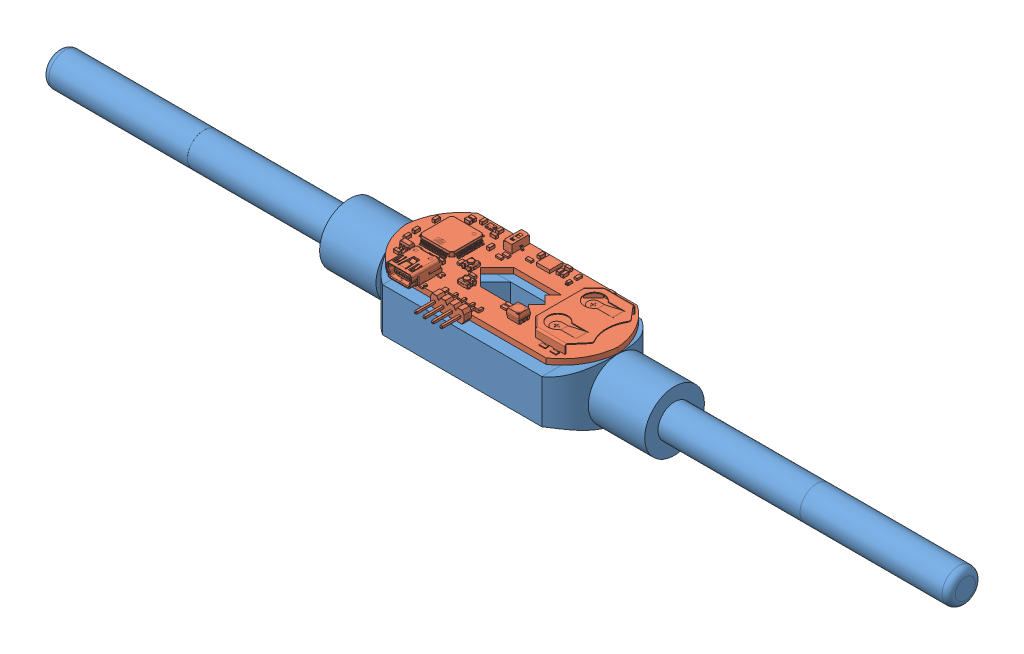
SolidWorks assembly VERTAP_ASSEMBLY, configuration Default. Lengths in mm.
Overall size (273.3 24.87 38.52).
2 component instances, 2 part files, 3 mates.
Components (placement in the parent):
- TAP_WRENCH-1: TAP_WRENCH [Default] at (3.0071 -32.375 20.4083) size (273.3 20.01 30)
- Vertap_v1_PCB-1: Vertap_v1_PCB [Default] at (3.0071 -21.566 20.4089) x (1 0 0) z (0 1 0) size (64 37.27 5.75)
Mates (geometry in assembly coordinates):
- Parallel1: parallel aligned: line of TAP_WRENCH-1 through (22.5071 -25.825 15.4083) axis (-1 0 0); line of Vertap_v1_PCB-1 through (13.0071 -21.566 15.4089) axis (-1 0 0)
- Coincident4: coincident aligned: plane of TAP_WRENCH-1 through (3.0071 -25.825 25.4083) normal (0 0 -1); plane of Vertap_v1_PCB-1 through (-1.4929 -23.2574 25.4089) normal (0 0 -1)
- Coincident5: coincident: point of assembly; line of assembly; moEndPointRef_w of TAP_WRENCH-1; line of Vertap_v1_PCB-1 through (-28.9929 -23.2574 20.4089) axis (0 1 0)
